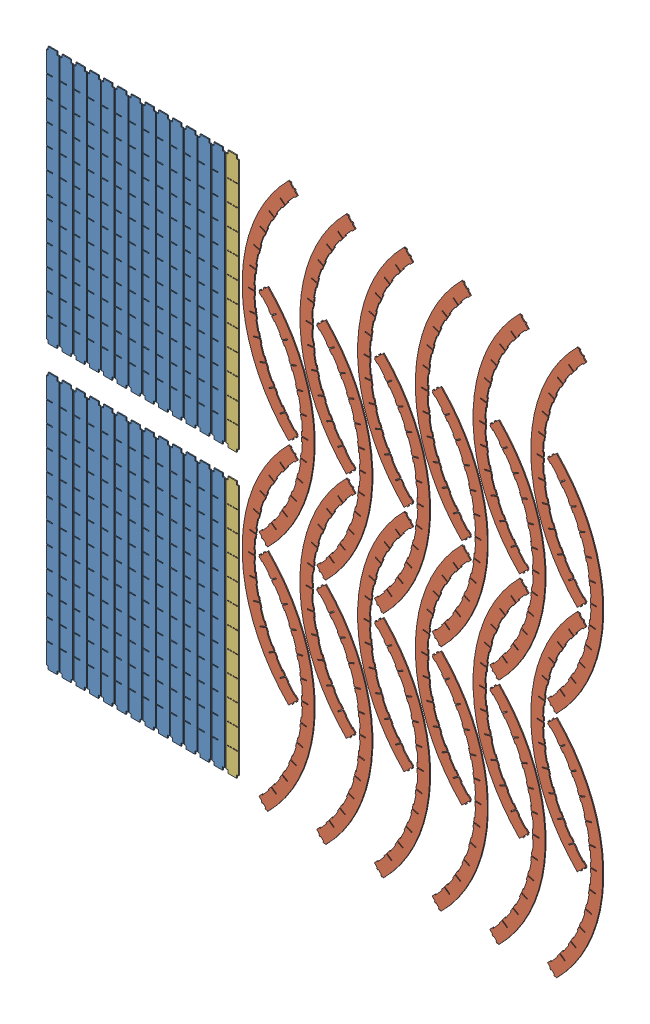
SolidWorks assembly 装配体3, configuration 默认. Lengths in mm.
Overall size (900 900 1.5).
52 component instances, 3 part files, 4 mates.
Components (placement in the parent):
- 格挡竖条-1: 格挡竖条 [默认] at (-433.6897 234.4832 0) size (20 410 1.5)
- 格挡竖条-2: 格挡竖条 [默认] at (-433.6897 -215.5168 0) size (20 410 1.5)
- 格挡竖条-3: 格挡竖条 [默认] at (-411.6897 234.4832 0) size (20 410 1.5)
- 格挡竖条-4: 格挡竖条 [默认] at (-411.6897 -215.5168 0) size (20 410 1.5)
- 格挡竖条-5: 格挡竖条 [默认] at (-389.6897 234.4832 0) size (20 410 1.5)
- 格挡竖条-6: 格挡竖条 [默认] at (-389.6897 -215.5168 0) size (20 410 1.5)
- 格挡竖条-7: 格挡竖条 [默认] at (-367.6897 234.4832 0) size (20 410 1.5)
- 格挡竖条-8: 格挡竖条 [默认] at (-367.6897 -215.5168 0) size (20 410 1.5)
- 格挡竖条-9: 格挡竖条 [默认] at (-345.6897 234.4832 0) size (20 410 1.5)
- 格挡竖条-10: 格挡竖条 [默认] at (-345.6897 -215.5168 0) size (20 410 1.5)
- 格挡竖条-11: 格挡竖条 [默认] at (-323.6897 234.4832 0) size (20 410 1.5)
- 格挡竖条-12: 格挡竖条 [默认] at (-323.6897 -215.5168 0) size (20 410 1.5)
- 格挡竖条-13: 格挡竖条 [默认] at (-301.6897 234.4832 0) size (20 410 1.5)
- 格挡竖条-14: 格挡竖条 [默认] at (-301.6897 -215.5168 0) size (20 410 1.5)
- 格挡竖条-15: 格挡竖条 [默认] at (-279.6897 234.4832 0) size (20 410 1.5)
- 格挡竖条-16: 格挡竖条 [默认] at (-279.6897 -215.5168 0) size (20 410 1.5)
- 格挡竖条-17: 格挡竖条 [默认] at (-257.6897 234.4832 0) size (20 410 1.5)
- 格挡竖条-18: 格挡竖条 [默认] at (-257.6897 -215.5168 0) size (20 410 1.5)
- 格挡竖条-19: 格挡竖条 [默认] at (-235.6897 234.4832 0) size (20 410 1.5)
- 格挡竖条-20: 格挡竖条 [默认] at (-235.6897 -215.5168 0) size (20 410 1.5)
- 格挡竖条-21: 格挡竖条 [默认] at (-213.6897 234.4832 0) size (20 410 1.5)
- 格挡竖条-22: 格挡竖条 [默认] at (-213.6897 -215.5168 0) size (20 410 1.5)
- 格挡竖条-23: 格挡竖条 [默认] at (-191.6897 234.4832 0) size (20 410 1.5)
- 格挡竖条-24: 格挡竖条 [默认] at (-191.6897 -215.5168 0) size (20 410 1.5)
- 格挡竖条-25: 格挡竖条 [默认] at (-169.6897 234.4832 0) size (20 410 1.5)
- 格挡竖条-26: 格挡竖条 [默认] at (-169.6897 -215.5168 0) size (20 410 1.5)
- 格挡横条-2: 格挡横条 [默认] at (123.0558 266.4869 0) x (0 -1 0) z (-1 0 0) size (359.02 1.5 88.19)
- 格挡横条-3: 格挡横条 [默认] at (-271.2362 103.3033 0) x (0 1 0) z (1 0 0) size (359.02 1.5 88.19)
- 格挡横条-4: 格挡横条 [默认] at (123.0558 -98.5131 0) x (0 -1 0) z (-1 0 0) size (359.02 1.5 88.19)
- 格挡横条-5: 格挡横条 [默认] at (215.0558 266.4869 0) x (0 -1 0) z (-1 0 0) size (359.02 1.5 88.19)
- 格挡横条-6: 格挡横条 [默认] at (215.0558 -98.5131 0) x (0 -1 0) z (-1 0 0) size (359.02 1.5 88.19)
- 格挡横条-7: 格挡横条 [默认] at (307.0558 266.4869 0) x (0 -1 0) z (-1 0 0) size (359.02 1.5 88.19)
- 格挡横条-8: 格挡横条 [默认] at (307.0558 -98.5131 0) x (0 -1 0) z (-1 0 0) size (359.02 1.5 88.19)
- 格挡横条-9: 格挡横条 [默认] at (-271.2362 -261.6967 0) x (0 1 0) z (1 0 0) size (359.02 1.5 88.19)
- 格挡横条-10: 格挡横条 [默认] at (-179.2362 103.3033 0) x (0 1 0) z (1 0 0) size (359.02 1.5 88.19)
- 格挡横条-11: 格挡横条 [默认] at (-179.2362 -261.6967 0) x (0 1 0) z (1 0 0) size (359.02 1.5 88.19)
- 格挡横条-12: 格挡横条 [默认] at (-87.2362 103.3033 0) x (0 1 0) z (1 0 0) size (359.02 1.5 88.19)
- 格挡横条-13: 格挡横条 [默认] at (-87.2362 -261.6967 0) x (0 1 0) z (1 0 0) size (359.02 1.5 88.19)
- 格挡横条-14: 格挡横条 [默认] at (399.0558 266.4869 0) x (0 -1 0) z (-1 0 0) size (359.02 1.5 88.19)
- 格挡横条-15: 格挡横条 [默认] at (399.0558 -98.5131 0) x (0 -1 0) z (-1 0 0) size (359.02 1.5 88.19)
- 格挡横条-16: 格挡横条 [默认] at (491.0558 266.4869 0) x (0 -1 0) z (-1 0 0) size (359.02 1.5 88.19)
- 格挡横条-17: 格挡横条 [默认] at (491.0558 -98.5131 0) x (0 -1 0) z (-1 0 0) size (359.02 1.5 88.19)
- 格挡横条-18: 格挡横条 [默认] at (583.0558 266.4869 0) x (0 -1 0) z (-1 0 0) size (359.02 1.5 88.19)
- 格挡横条-19: 格挡横条 [默认] at (583.0558 -98.5131 0) x (0 -1 0) z (-1 0 0) size (359.02 1.5 88.19)
- 格挡横条-20: 格挡横条 [默认] at (4.7638 103.3033 0) x (0 1 0) z (1 0 0) size (359.02 1.5 88.19)
- 格挡横条-21: 格挡横条 [默认] at (4.7638 -261.6967 0) x (0 1 0) z (1 0 0) size (359.02 1.5 88.19)
- 格挡横条-22: 格挡横条 [默认] at (96.7638 103.3033 0) x (0 1 0) z (1 0 0) size (359.02 1.5 88.19)
- 格挡横条-23: 格挡横条 [默认] at (96.7638 -261.6967 0) x (0 1 0) z (1 0 0) size (359.02 1.5 88.19)
- 格挡横条-24: 格挡横条 [默认] at (188.7638 103.3033 0) x (0 1 0) z (1 0 0) size (359.02 1.5 88.19)
- 格挡横条-25: 格挡横条 [默认] at (188.7638 -261.6967 0) x (0 1 0) z (1 0 0) size (359.02 1.5 88.19)
- 格挡竖衔接条-1: 格挡竖衔接条 [默认] at (-147.2997 234.4417 0) size (20 410 1.5)
- 格挡竖衔接条-2: 格挡竖衔接条 [默认] at (-147.2997 -215.5583 0) size (20 410 1.5)
Mates (geometry in assembly coordinates):
- 重合1: coincident anti-aligned: plane of 格挡竖条-1 through (-433.6897 234.4832 0) normal (0 0 -1)
- 重合3: coincident anti-aligned: plane of 格挡横条-2 through (123.0558 266.4869 0) normal (0 0 -1)
- 重合4: coincident anti-aligned: plane of 格挡横条-3 through (-271.2362 103.3033 0) normal (0 0 -1)
- 重合5: coincident anti-aligned: plane of 格挡竖衔接条-1 through (-147.2997 234.4417 0) normal (0 0 -1)
